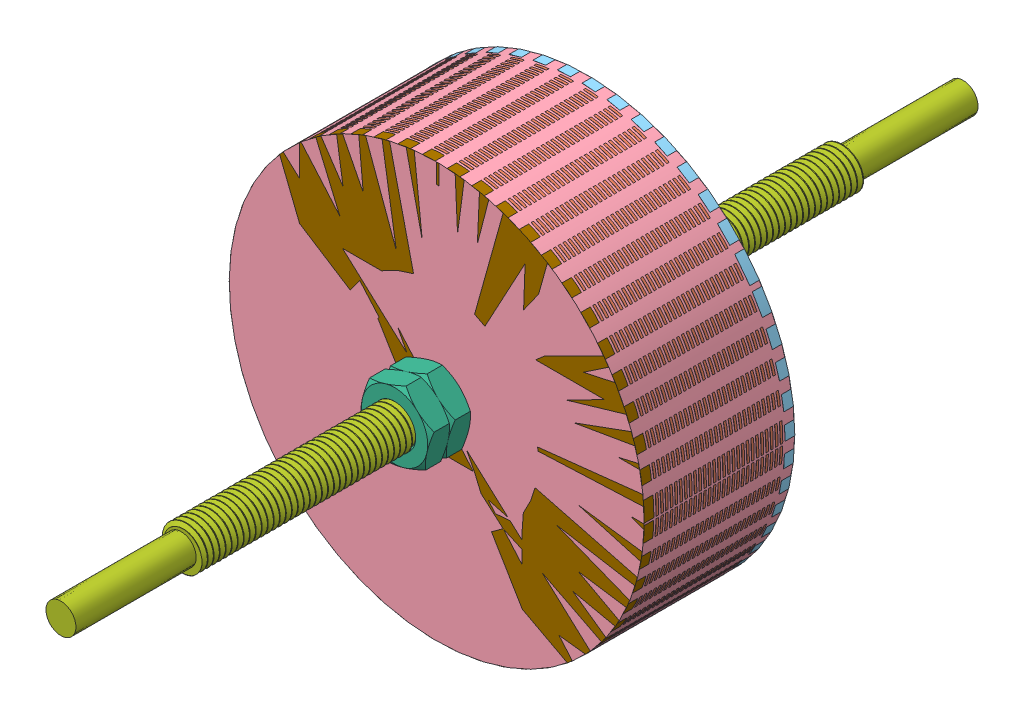
SolidWorks assembly rotor, configuration Default. Lengths in mm.
Overall size (194.65 194.65 300).
73 component instances, 9 part files, 39 mates.
Components (placement in the parent):
- spacer 1-38: spacer 1 [Default] at (195.0988 -33.2277 -14.8998) size (102.08 102.08 0.8)
- disk 1-1: disk 1 [Default] at (195.0988 -33.2277 -15.6998) size (138 138 0.8)
- spacer 1-2: spacer 1 [Default] at (195.0988 -33.2277 -16.4998) size (102.08 102.08 0.8)
- disk 1-2: disk 1 [Default] at (195.0988 -33.2277 -17.2873) size (138 138 0.8)
- disk 1-3: disk 1 [Default] at (195.0988 -33.2277 -18.8748) size (138 138 0.8)
- disk 1-4: disk 1 [Default] at (195.0988 -33.2277 -20.4623) size (138 138 0.8)
- disk 1-5: disk 1 [Default] at (195.0988 -33.2277 -22.0498) size (138 138 0.8)
- disk 1-6: disk 1 [Default] at (195.0988 -33.2277 -23.6373) size (138 138 0.8)
- disk 1-7: disk 1 [Default] at (195.0988 -33.2277 -25.2248) size (138 138 0.8)
- disk 1-8: disk 1 [Default] at (195.0988 -33.2277 -26.8123) size (138 138 0.8)
- disk 1-9: disk 1 [Default] at (195.0988 -33.2277 -28.3998) size (138 138 0.8)
- disk 1-10: disk 1 [Default] at (195.0988 -33.2277 -29.9873) size (138 138 0.8)
- disk 1-11: disk 1 [Default] at (195.0988 -33.2277 -31.5748) size (138 138 0.8)
- disk 1-12: disk 1 [Default] at (195.0988 -33.2277 -33.1623) size (138 138 0.8)
- disk 1-13: disk 1 [Default] at (195.0988 -33.2277 -34.7498) size (138 138 0.8)
- spacer 1-24: spacer 1 [Default] at (195.0988 -33.2277 -18.0873) size (102.08 102.08 0.8)
- spacer 1-25: spacer 1 [Default] at (195.0988 -33.2277 -19.6748) size (102.08 102.08 0.8)
- spacer 1-26: spacer 1 [Default] at (195.0988 -33.2277 -21.2623) size (102.08 102.08 0.8)
- spacer 1-27: spacer 1 [Default] at (195.0988 -33.2277 -22.8498) size (102.08 102.08 0.8)
- spacer 1-28: spacer 1 [Default] at (195.0988 -33.2277 -24.4373) size (102.08 102.08 0.8)
- spacer 1-29: spacer 1 [Default] at (195.0988 -33.2277 -26.0248) size (102.08 102.08 0.8)
- spacer 1-30: spacer 1 [Default] at (195.0988 -33.2277 -27.6123) size (102.08 102.08 0.8)
- spacer 1-31: spacer 1 [Default] at (195.0988 -33.2277 -29.1998) size (102.08 102.08 0.8)
- spacer 1-32: spacer 1 [Default] at (195.0988 -33.2277 -30.7873) size (102.08 102.08 0.8)
- spacer 1-33: spacer 1 [Default] at (195.0988 -33.2277 -32.3748) size (102.08 102.08 0.8)
- spacer 1-34: spacer 1 [Default] at (195.0988 -33.2277 -33.9623) size (102.08 102.08 0.8)
- spacer 1-35: spacer 1 [Default] at (195.0988 -33.2277 -35.5498) size (102.08 102.08 0.8)
- keyway-1: keyway [Default] at (193.6238 -43.2777 -57.7998) x (0 0 1) z (-1 0 0) size (46.9 3 3)
- rotating part for simulation^rotor-1: rotating part for simulation^rotor [Default] at (195.0988 -33.2277 -10.8998) x (-0.756485 -0.654012 0) z (0 0 1) size (138 138 50) (virtual)
- disk 1-14: disk 1 [Default] at (195.0988 -33.2277 -36.3373) size (138 138 0.8)
- disk 1-15: disk 1 [Default] at (195.0988 -33.2277 -37.9248) size (138 138 0.8)
- disk 1-16: disk 1 [Default] at (195.0988 -33.2277 -39.5123) size (138 138 0.8)
- disk 1-17: disk 1 [Default] at (195.0988 -33.2277 -41.0998) size (138 138 0.8)
- disk 1-18: disk 1 [Default] at (195.0988 -33.2277 -42.6873) size (138 138 0.8)
- disk 1-19: disk 1 [Default] at (195.0988 -33.2277 -44.2748) size (138 138 0.8)
- disk 1-20: disk 1 [Default] at (195.0988 -33.2277 -45.8623) size (138 138 0.8)
- disk 1-21: disk 1 [Default] at (195.0988 -33.2277 -47.4498) size (138 138 0.8)
- disk 1-22: disk 1 [Default] at (195.0988 -33.2277 -49.0373) size (138 138 0.8)
- disk 1-23: disk 1 [Default] at (195.0988 -33.2277 -50.6248) size (138 138 0.8)
- disk 1-24: disk 1 [Default] at (195.0988 -33.2277 -52.2123) size (138 138 0.8)
- disk 1-25: disk 1 [Default] at (195.0988 -33.2277 -53.7998) size (138 138 0.8)
- spacer 1-39: spacer 1 [Default] at (195.0988 -33.2277 -37.1373) size (102.08 102.08 0.8)
- spacer 1-40: spacer 1 [Default] at (195.0988 -33.2277 -40.3123) size (102.08 102.08 0.8)
- spacer 1-41: spacer 1 [Default] at (195.0988 -33.2277 -41.8998) size (102.08 102.08 0.8)
- spacer 1-42: spacer 1 [Default] at (195.0988 -33.2277 -43.4873) size (102.08 102.08 0.8)
- spacer 1-43: spacer 1 [Default] at (195.0988 -33.2277 -45.0748) size (102.08 102.08 0.8)
- spacer 1-44: spacer 1 [Default] at (195.0988 -33.2277 -46.6623) size (102.08 102.08 0.8)
- spacer 1-45: spacer 1 [Default] at (195.0988 -33.2277 -48.2498) size (102.08 102.08 0.8)
- spacer 1-46: spacer 1 [Default] at (195.0988 -33.2277 -49.8373) size (102.08 102.08 0.8)
- spacer 1-47: spacer 1 [Default] at (195.0988 -33.2277 -51.4248) size (102.08 102.08 0.8)
- spacer 1-48: spacer 1 [Default] at (195.0988 -33.2277 -53.0123) size (102.08 102.08 0.8)
- spacer 1-49: spacer 1 [Default] at (195.0988 -33.2277 -54.5998) size (102.08 102.08 0.8)
- disk x-1: disk x [Default] at (195.0988 -33.2277 -60.9748) x (-1 0 0) z (0 0 1) size (138 138 3.2)
- spacer 1-50: spacer 1 [Default] at (195.0988 -33.2277 -38.7248) size (102.08 102.08 0.8)
- 90710A135_TYPE 18-8 SS THIN HEX NUT - DIN 439B-1: 90710A135_TYPE 18-8 SS THIN HEX NUT - DIN 439B [90710A135] at (195.0988 -33.2277 -7.3998) x (0.293352 -0.956004 0) z (0.956004 0.293352 0) size (22 8.54 25.4)
- 90710A135_TYPE 18-8 SS THIN HEX NUT - DIN 439B-2: 90710A135_TYPE 18-8 SS THIN HEX NUT - DIN 439B [90710A135] at (195.0988 -33.2277 -0.3998) x (-0.9746 0.223952 0) z (0.223952 0.9746 0) size (22 8.54 25.4)
- axle-1: axle [90024A005] at (195.0988 -33.2277 -35.9348) x (0 0 -1) z (-0.143036 -0.989718 0) size (300 14.46 16.17)
- 90710A135_TYPE 18-8 SS THIN HEX NUT - DIN 439B-3: 90710A135_TYPE 18-8 SS THIN HEX NUT - DIN 439B [90710A135] at (195.0988 -33.2277 -71.4748) x (-0.9746 0.223952 0) z (0.223952 0.9746 0) size (22 8.54 25.4)
- 90710A135_TYPE 18-8 SS THIN HEX NUT - DIN 439B-4: 90710A135_TYPE 18-8 SS THIN HEX NUT - DIN 439B [90710A135] at (195.0988 -33.2277 -64.4748) x (-0.9746 0.223952 0) z (0.223952 0.9746 0) size (22 8.54 25.4)
- item_0060029_countersunk_screw_din_7991_m5x50_details_3-1: item_0060029_countersunk_screw_din_7991_m5x50_details_3 [Default] at (255.0988 -33.2277 -10.8998) x (-0.092036 -0.995756 0) z (0 0 1) size (10 10 50)
- item_0060029_countersunk_screw_din_7991_m5x50_details_3-2: item_0060029_countersunk_screw_din_7991_m5x50_details_3 [Default] at (215.7488 -33.2277 -10.8998) x (-0.092036 -0.995756 0) z (0 0 1) size (10 10 50)
- disk 1-26: disk 1 [Default] at (195.0988 -33.2277 -55.3873) size (138 138 0.8)
- disk 1-27: disk 1 [Default] at (195.0988 -33.2277 -56.9748) size (138 138 0.8)
- spacer 1-51: spacer 1 [Default] at (195.0988 -33.2277 -56.1873) size (102.08 102.08 0.8)
- spacer 1-52: spacer 1 [Default] at (195.0988 -33.2277 -57.7748) size (102.08 102.08 0.8)
- disk 0-1: disk 0 [Default] at (195.0988 -33.2277 -14.0998) size (138 138 3.2)
- item_0060029_countersunk_screw_din_7991_m5x50_details_3-9: item_0060029_countersunk_screw_din_7991_m5x50_details_3 [Default] at (195.0988 26.7723 -10.8998) x (0.995756 -0.092036 0) z (0 0 1) size (10 10 50)
- item_0060029_countersunk_screw_din_7991_m5x50_details_3-10: item_0060029_countersunk_screw_din_7991_m5x50_details_3 [Default] at (135.0988 -33.2277 -10.8998) x (0.092036 0.995756 0) z (0 0 1) size (10 10 50)
- item_0060029_countersunk_screw_din_7991_m5x50_details_3-11: item_0060029_countersunk_screw_din_7991_m5x50_details_3 [Default] at (195.0988 -93.2277 -10.8998) x (-0.995756 0.092036 0) z (0 0 1) size (10 10 50)
- item_0060029_countersunk_screw_din_7991_m5x50_details_3-12: item_0060029_countersunk_screw_din_7991_m5x50_details_3 [Default] at (195.0988 -12.5777 -10.8998) x (0.995756 -0.092036 0) z (0 0 1) size (10 10 50)
- item_0060029_countersunk_screw_din_7991_m5x50_details_3-13: item_0060029_countersunk_screw_din_7991_m5x50_details_3 [Default] at (174.4488 -33.2277 -10.8998) x (0.092036 0.995756 0) z (0 0 1) size (10 10 50)
- item_0060029_countersunk_screw_din_7991_m5x50_details_3-14: item_0060029_countersunk_screw_din_7991_m5x50_details_3 [Default] at (195.0988 -53.8777 -10.8998) x (-0.995756 0.092036 0) z (0 0 1) size (10 10 50)
- keyway-2: keyway [Default] at (193.6238 -26.1777 -57.7998) x (0 0 1) z (-1 0 0) size (46.9 3 3)
Mates (geometry in assembly coordinates):
- Coincident3: coincident anti-aligned: plane of disk 1-1 through (195.0988 -33.2277 -15.6998) normal (0 0 -1); plane of spacer 1-2 through (195.0988 -33.2277 -15.6998) normal (0 0 1)
- Coincident15: coincident aligned: plane of disk 1-21 through (-1.5 7 94.2055) normal (1 0 0); plane of ? through (-1.5 0 95.031) normal (1 0 0)
- Coincident31: coincident anti-aligned: plane of disk 1-1 through (195.0988 -33.2277 -14.8998) normal (0 0 1); plane of spacer 1-38 through (195.0988 -33.2277 -14.8998) normal (0 0 -1)
- Concentric15: concentric aligned: cylinder of spacer 1-38 through (195.0988 -33.2277 -14.0998) axis (0 0 -1) radius 7; cylinder of spacer 1-2 through (195.0988 -33.2277 -15.6998) axis (0 0 -1) radius 7
- Coincident49: coincident anti-aligned: plane of disk 1-1 through (196.6238 -23.1777 -14.8998) normal (-1 0 0); plane of keyway-1 through (196.6238 -40.2777 -57.7998) normal (1 0 0)
- Parallel2: parallel anti-aligned: plane of keyway-1 through (196.6238 -40.2777 -57.7998) normal (1 0 0); plane of disk x-1 through (196.6238 -23.1777 -57.7748) normal (-1 0 0)
- Coincident65: coincident aligned: plane of 90710A135_TYPE 18-8 SS THIN HEX NUT - DIN 439B-1 through (192.2543 -45.6068 -10.8998) normal (-0.681248 -0.732053 0); plane of 90710A135_TYPE 18-8 SS THIN HEX NUT - DIN 439B-2 through (182.9559 -36.9538 3.1002) normal (-0.681248 -0.732053 0)
- Coincident66: coincident anti-aligned: circle of 90710A135_TYPE 18-8 SS THIN HEX NUT - DIN 439B-1; circle of 90710A135_TYPE 18-8 SS THIN HEX NUT - DIN 439B-2
- Coincident67: coincident aligned: plane of spacer 1-38 through (196.6238 -33.2277 -14.0998) normal (-1 0 0); plane of disk 1-1 through (196.6238 -43.2777 -14.8998) normal (-1 0 0)
- Coincident70: coincident aligned: plane of 90710A135_TYPE 18-8 SS THIN HEX NUT - DIN 439B-1 through (197.9434 -20.8486 -10.8998) normal (0.681248 0.732053 0); plane of 90710A135_TYPE 18-8 SS THIN HEX NUT - DIN 439B-4 through (207.2417 -29.5016 -60.9748) normal (0.681248 0.732053 0)
- Coincident72: coincident anti-aligned: plane of 90710A135_TYPE 18-8 SS THIN HEX NUT - DIN 439B-3 through (204.3972 -41.8807 -67.9748) normal (0 0 1); plane of 90710A135_TYPE 18-8 SS THIN HEX NUT - DIN 439B-4 through (204.3972 -41.8807 -67.9748) normal (0 0 -1)
- Concentric37: concentric aligned: circle of 90710A135_TYPE 18-8 SS THIN HEX NUT - DIN 439B-3; circle of 90710A135_TYPE 18-8 SS THIN HEX NUT - DIN 439B-4
- Concentric38: concentric aligned: circle of 90710A135_TYPE 18-8 SS THIN HEX NUT - DIN 439B-2; circle of 90710A135_TYPE 18-8 SS THIN HEX NUT - DIN 439B-3
- Coincident77: coincident aligned: plane of 90710A135_TYPE 18-8 SS THIN HEX NUT - DIN 439B-3 through (207.2417 -29.5016 -67.9748) normal (0.681248 0.732053 0); plane of 90710A135_TYPE 18-8 SS THIN HEX NUT - DIN 439B-4 through (207.2417 -29.5016 -60.9748) normal (0.681248 0.732053 0)
- Coincident80: coincident anti-aligned: plane of disk x-1 through (195.0988 -33.2277 -60.9748) normal (0 0 -1); plane of 90710A135_TYPE 18-8 SS THIN HEX NUT - DIN 439B-4 through (204.3972 -41.8807 -60.9748) normal (0 0 1)
- Coincident89: coincident anti-aligned: plane of disk x-1 through (195.0988 -33.2277 -57.7748) normal (0 0 1); plane of spacer 1-52 through (195.0988 -33.2277 -57.7748) normal (0 0 -1)
- Distance2: distance = 70.965 mm aligned: plane of axle-1 through (195.0988 -33.2277 74.0652) normal (0 0 1); plane of 90710A135_TYPE 18-8 SS THIN HEX NUT - DIN 439B-2 through (204.3972 -41.8807 3.1002) normal (0 0 1)
- Concentric41: concentric aligned: cylinder of axle-1 through (195.0988 -33.2277 74.0652) axis (0 0 1) radius 5; circle of disk 0-1
- Coincident90: coincident anti-aligned: plane of spacer 1-38 through (195.0988 -33.2277 -14.0998) normal (0 0 1); plane of disk 0-1 through (195.0988 -33.2277 -14.0998) normal (0 0 -1)
- Concentric42: concentric aligned: circle of disk 1-1; cylinder of axle-1 through (195.0988 -33.2277 74.0652) axis (0 0 1) radius 5
- Concentric43: concentric aligned: circle of disk x-1; cylinder of axle-1 through (195.0988 -33.2277 74.0652) axis (0 0 1) radius 5
- Concentric44: concentric aligned: circle of 90710A135_TYPE 18-8 SS THIN HEX NUT - DIN 439B-2; cylinder of axle-1 through (195.0988 -33.2277 74.0652) axis (0 0 1) radius 5
- Coincident91: coincident anti-aligned: plane of 90710A135_TYPE 18-8 SS THIN HEX NUT - DIN 439B-1 through (185.8005 -24.5747 -10.8998) normal (0 0 -1); plane of disk 0-1 through (195.0988 -33.2277 -10.8998) normal (0 0 1)
- Concentric45: concentric anti-aligned: circle of spacer 1-38; cylinder of axle-1 through (195.0988 -33.2277 74.0652) axis (0 0 1) radius 5
- Concentric46: concentric anti-aligned: cylinder of item_0060029_countersunk_screw_din_7991_m5x50_details_3-1 through (255.0988 -33.2277 -60.8998) axis (0 0 1) radius 2.5; cylinder of disk 0-1 through (255.0988 -33.2277 -10.8998) axis (0 0 -1) radius 2.505
- Coincident92: coincident aligned: plane of item_0060029_countersunk_screw_din_7991_m5x50_details_3-1 through (255.0988 -33.2277 -10.8998) normal (0 0 1); plane of disk 0-1 through (195.0988 -33.2277 -10.8998) normal (0 0 1)
- Concentric47: concentric anti-aligned: cylinder of item_0060029_countersunk_screw_din_7991_m5x50_details_3-2 through (215.7488 -33.2277 -60.8998) axis (0 0 1) radius 2.5; cylinder of disk 0-1 through (215.7488 -33.2277 -10.8998) axis (0 0 -1) radius 2.505
- Coincident93: coincident aligned: plane of item_0060029_countersunk_screw_din_7991_m5x50_details_3-2 through (215.7488 -33.2277 -10.8998) normal (0 0 1); plane of disk 0-1 through (195.0988 -33.2277 -10.8998) normal (0 0 1)
- Coincident94: coincident aligned: plane of spacer 1-38 through (196.6238 -33.2277 -14.0998) normal (-1 0 0); plane of disk 0-1 through (196.6238 -43.2777 -10.8998) normal (-1 0 0)
- Coincident95: coincident aligned: plane of spacer 1-2 through (196.6238 -33.2277 -15.6998) normal (-1 0 0); plane of disk 0-1 through (196.6238 -43.2777 -10.8998) normal (-1 0 0)
- Coincident96: coincident anti-aligned: plane of keyway-1 through (196.6238 -40.2777 -57.7998) normal (1 0 0); plane of disk 0-1 through (196.6238 -43.2777 -10.8998) normal (-1 0 0)
- Coincident97: coincident aligned: plane of keyway-1 through (193.6238 -40.2777 -10.8998) normal (0 0 1); plane of disk 0-1 through (195.0988 -33.2277 -10.8998) normal (0 0 1)
- Coincident98: coincident anti-aligned: plane of keyway-1 through (193.6238 -43.2777 -57.7998) normal (0 -1 0); plane of disk 0-1 through (193.5738 -43.2777 -10.8998) normal (0 1 0)
- Coincident102: coincident aligned: plane of disk 0-1 through (195.0988 -33.2277 -10.8998) normal (0 0 1); plane of keyway-2 through (193.6238 -23.1777 -10.8998) normal (0 0 1)
- Coincident103: coincident anti-aligned: plane of disk 0-1 through (196.6238 -23.1777 -10.8998) normal (-1 0 0); plane of keyway-2 through (196.6238 -23.1777 -57.7998) normal (1 0 0)
- Coincident104: coincident anti-aligned: plane of disk 0-1 through (193.5738 -23.1777 -10.8998) normal (0 -1 0); plane of keyway-2 through (193.6238 -23.1777 -57.7998) normal (0 1 0)
- Parallel3: parallel anti-aligned: plane of keyway-1 through (193.6238 -43.2777 -57.7998) normal (0 -1 0); plane of assembly through (0 0 0) normal (0 1 0)
- Concentric48: concentric aligned: circle of rotating part for simulation^rotor-1; cylinder of axle-1 through (195.0988 -33.2277 74.0652) axis (0 0 1) radius 5
- Coincident105: coincident aligned: plane of rotating part for simulation^rotor-1 through (195.0988 -33.2277 -10.8998) normal (0 0 1); plane of disk 0-1 through (195.0988 -33.2277 -10.8998) normal (0 0 1)
